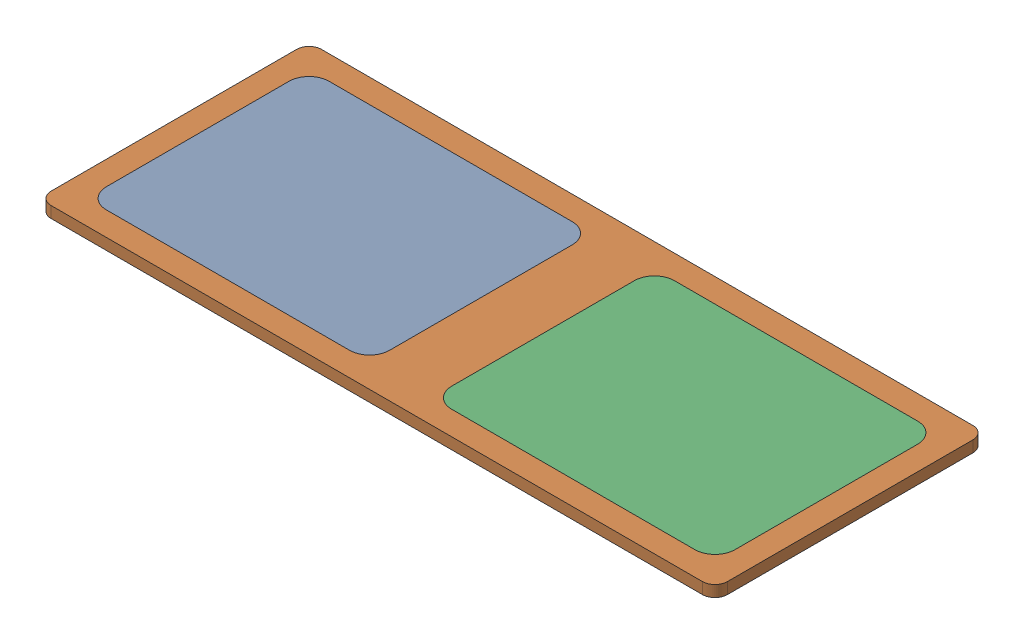
SolidWorks assembly lid_assembly, configuration Default. Lengths in mm.
Overall size (538.7 9 215.4).
3 component instances, 2 part files, 3 mates.
Components (placement in the parent):
- Lid_window-1: Lid_window [Default] at (0 60.5 -98.7) x (-1 0 0) z (0 1 0) size (225.62 177.4 6)
- lid_rectangular-1: lid_rectangular [Default] at (0 66.5 -98.7) x (1 0 0) z (0 -1 0) size (538.7 215.4 9)
- Lid_window-2: Lid_window [Default] at (0 66.5 -98.7) x (1 0 0) z (0 -1 0) size (225.62 177.4 6)
Mates (geometry in assembly coordinates):
- Coincident134: coincident anti-aligned: plane of lid_rectangular-1 through (234.35 60.5 -72.7) normal (0 1 0); plane of Lid_window-2 through (234.35 60.5 -72.7) normal (0 -1 0)
- Concentric7: concentric aligned: cylinder of lid_rectangular-1 through (234.35 60.5 -72.7) axis (0 1 0) radius 16; cylinder of Lid_window-2 through (234.35 60.5 -72.7) axis (0 1 0) radius 16
- Coincident136: coincident anti-aligned: plane of lid_rectangular-1 through (234.35 60.5 88.7) normal (0 0 -1); plane of Lid_window-2 through (234.35 60.5 88.7) normal (0 0 1)
